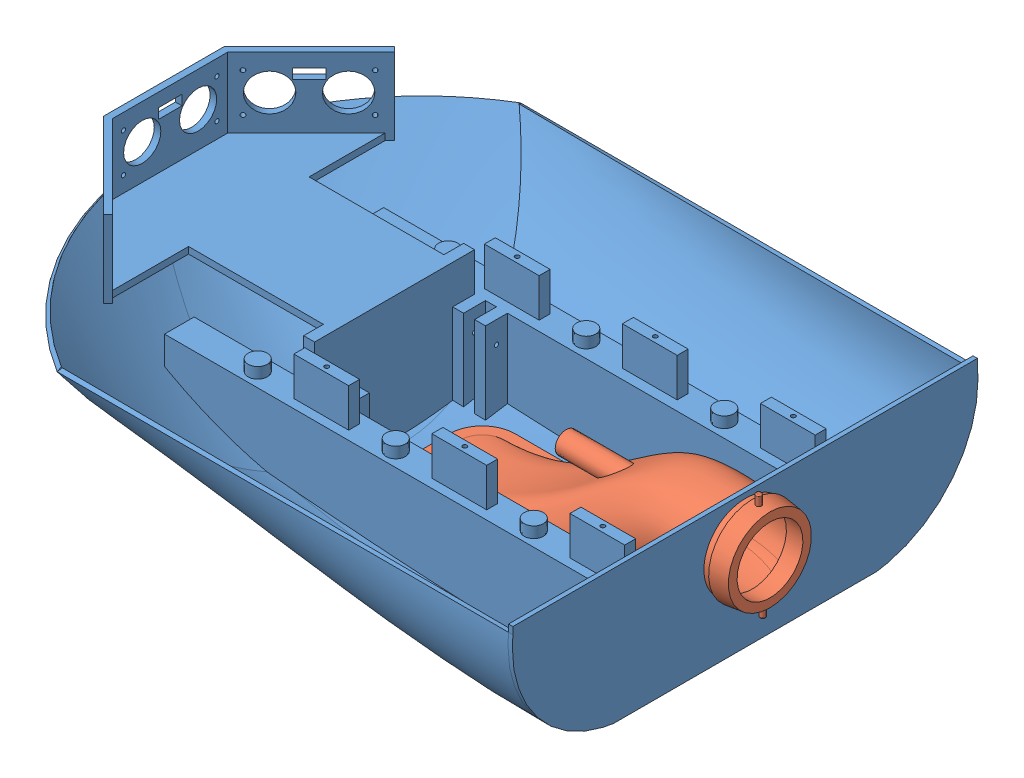
SolidWorks assembly BaseAssemble, configuration Default. Lengths in mm.
Overall size (283.43 94.17 217.67).
2 component instances, 2 part files, 3 mates.
Components (placement in the parent):
- BottonCoverNew3-1: BottonCoverNew3 [Default] at (173.3525 109.8581 193.1945) size (272.39 94.17 217.67)
- Turbine sketch-1: Turbine sketch [Default] at (153.3525 56.8581 193.1945) x (0 -1 0) z (1 0 0) size (64 54 158.04)
Mates (geometry in assembly coordinates):
- Coincident1: coincident anti-aligned: plane of BottonCoverNew3-1 through (158.3525 48.6775 205.1945) normal (-1 0 0); plane of Turbine sketch-1 through (158.3525 51.8581 181.1945) normal (1 0 0)
- Coincident2: coincident anti-aligned: plane of BottonCoverNew3-1 through (43.3525 48.6775 220.1945) normal (0 0 -1); plane of Turbine sketch-1 through (143.3525 51.8581 220.1945) normal (0 0 1)
- Tangent1: tangent: plane of assembly; face of BottonCoverNew3-1; plane of Turbine sketch-1 through (143.3525 51.8581 205.1945) normal (0 -1 0)
